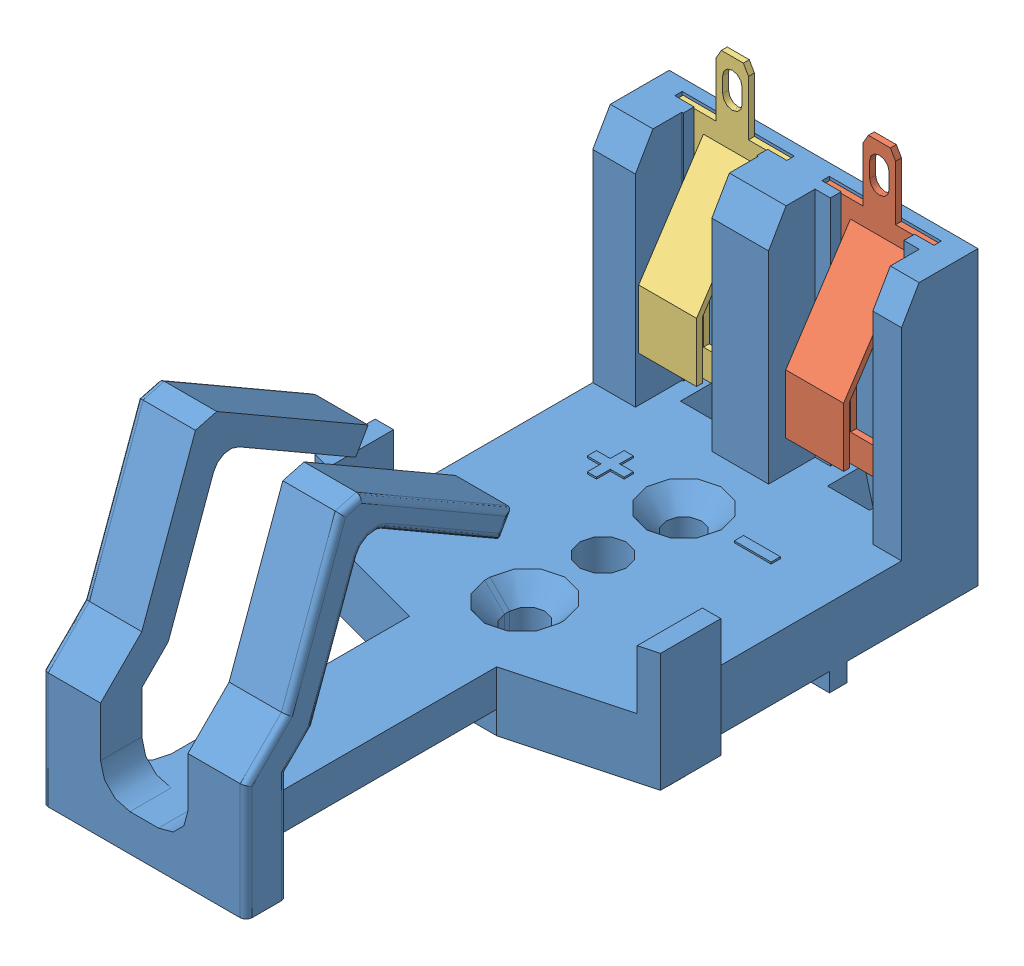
SolidWorks assembly bx0033, configuration Default. Lengths in mm.
Overall size (29.85 36.83 58.82).
3 component instances, 3 part files, 2 mates.
Components (placement in the parent):
- bx0033_01-1: bx0033_01 [Default] at origin size (29.85 30.4 58.82)
- bx0033_02-1: bx0033_02 [Default] at origin size (9.53 36.83 6.65)
- bx0033_03-1: bx0033_03 [Default] at origin size (9.53 36.83 6.65)
Mates (geometry in assembly coordinates):
- Concentric1: concentric: circle of bx0033_01-1; circle of BatteryHolder_M3-1
- Coincident1: coincident aligned: plane of bx0033_01-1 through (0 5.16 0) normal (0 1 0); plane of BatteryHolder_M3-1 through (0 5.16 27.08) normal (0 1 0)
